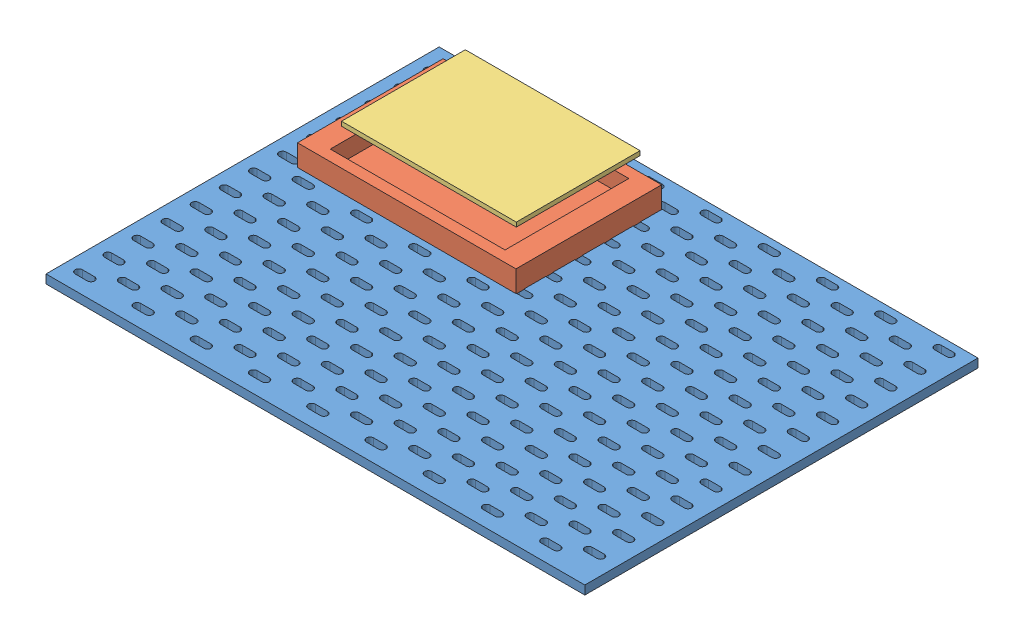
SolidWorks assembly МакетСБ, configuration По умолчанию. Lengths in mm.
Overall size (370 34.94 270).
4 component instances, 3 part files, 0 mates.
Components (placement in the parent):
- Плита-1: Плита [По умолчанию] at origin size (370 6 270)
- МакетА-1: МакетА [По умолчанию] at (-86.9149 5.7241 -64.6262) size (150 29.21 100)
  - КорпусА-1: КорпусА [По умолчанию] at origin size (150 15 100)
  - КрышкаА-1: КрышкаА [По умолчанию] at (1.5107 26.2146 -6.2279) size (120 3 85)
